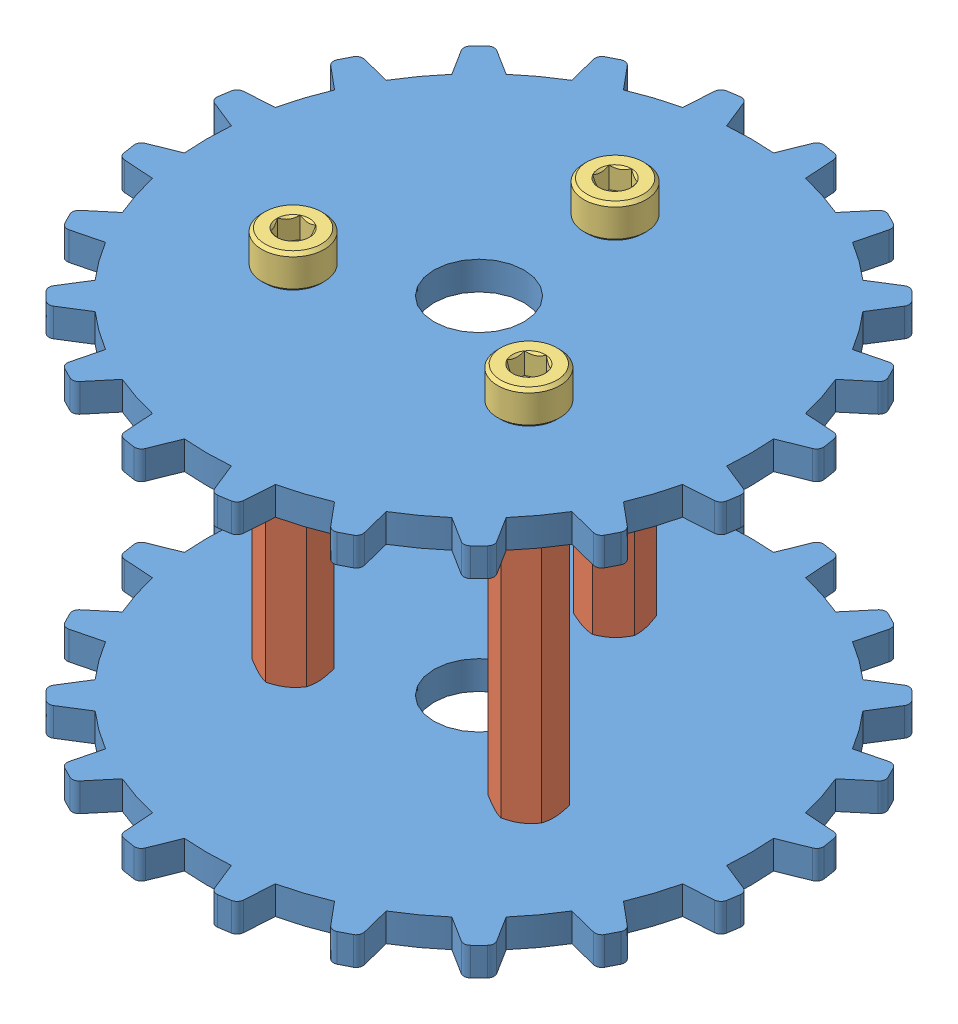
SolidWorks assembly DrivingWheelAssem, configuration Default. Lengths in mm.
Overall size (53.49 39.29 53.49).
11 component instances, 3 part files, 26 mates.
Components (placement in the parent):
- DrivingWheel-1: DrivingWheel [Default] at origin size (53.49 2.5 53.49)
- DrivingWheel-2: DrivingWheel [Default] at (0 30.5 0) size (53.49 2.5 53.49)
- M3_28MM_Standoff-1: M3_28MM_Standoff [95947A517] at (-10.3923 14 6) x (-0.440762 0 0.897624) z (0 -1 0) size (4.5 5.2 28.67)
- M3_8MM_SocketHead-1: M3_8MM_SocketHead [91292A112] at (-10.3923 22.5 6) x (0.889266 0 -0.457391) z (0 -1 0) size (5.5 5.5 11.58)
- M3_28MM_Standoff-2: M3_28MM_Standoff [95947A517] at (10.3923 14 6) x (-0.541432 0 -0.840745) z (0 -1 0) size (4.5 5.2 28.67)
- M3_8MM_SocketHead-2: M3_8MM_SocketHead [91292A112] at (10.3923 22.5 6) x (0.997541 0 0.070084) z (0 -1 0) size (5.5 5.5 11.58)
- M3_28MM_Standoff-3: M3_28MM_Standoff [95947A517] at (0 14 -12) x (-0.674924 0 -0.737887) z (0 -1 0) size (4.5 5.2 28.67)
- M3_8MM_SocketHead-3: M3_8MM_SocketHead [91292A112] at (0 22.5 -12) x (1 0 0) z (0 -1 0) size (5.5 5.5 11.58)
- M3_8MM_SocketHead-4: M3_8MM_SocketHead [91292A112] at (10.3923 5.5 6) x (1 0 0) z (0 1 0) size (5.5 5.5 11.58)
- M3_8MM_SocketHead-5: M3_8MM_SocketHead [91292A112] at (-10.3923 5.5 6) x (0.298331 0 0.954463) z (0 1 0) size (5.5 5.5 11.58)
- M3_8MM_SocketHead-6: M3_8MM_SocketHead [91292A112] at (0 5.5 -12) x (1 0 0) z (0 1 0) size (5.5 5.5 11.58)
Mates (geometry in assembly coordinates):
- Concentric1: concentric aligned: circle of DrivingWheel-1; circle of DrivingWheel-2
- Concentric2: concentric aligned: circle of DrivingWheel-1; circle of DrivingWheel-2
- Concentric3: concentric aligned: circle of DrivingWheel-1; circle of M3_28MM_Standoff-3
- Concentric4: concentric aligned: circle of DrivingWheel-1; circle of M3_28MM_Standoff-1
- Concentric5: concentric aligned: circle of DrivingWheel-1; circle of M3_28MM_Standoff-2
- Coincident3: coincident anti-aligned: plane of DrivingWheel-1 through (0 0 0) normal (0 1 0); plane of M3_28MM_Standoff-1 through (-12.7244 0 4.8549) normal (0 -1 0)
- Coincident4: coincident anti-aligned: plane of DrivingWheel-1 through (0 0 0) normal (0 1 0); plane of M3_28MM_Standoff-2 through (12.5766 0 4.5933) normal (0 -1 0)
- Coincident5: coincident anti-aligned: plane of DrivingWheel-1 through (0 0 0) normal (0 1 0); plane of M3_28MM_Standoff-3 through (1.9171 0 -13.7535) normal (0 -1 0)
- Coincident6: coincident anti-aligned: plane of DrivingWheel-2 through (0 28 0) normal (0 -1 0); plane of M3_28MM_Standoff-1 through (-12.7244 28 4.8549) normal (0 1 0)
- Coincident7: coincident anti-aligned: plane of DrivingWheel-2 through (0 30.5 0) normal (0 1 0); plane of M3_8MM_SocketHead-1 through (-10.3923 30.5 6) normal (0 -1 0)
- Concentric7: concentric anti-aligned: circle of DrivingWheel-2; circle of M3_8MM_SocketHead-2
- Coincident8: coincident anti-aligned: plane of DrivingWheel-2 through (0 30.5 0) normal (0 1 0); plane of M3_8MM_SocketHead-2 through (10.3923 30.5 6) normal (0 -1 0)
- Coincident9: coincident anti-aligned: plane of DrivingWheel-2 through (0 30.5 0) normal (0 1 0); plane of M3_8MM_SocketHead-3 through (0 30.5 -12) normal (0 -1 0)
- Concentric8: concentric aligned: circle of DrivingWheel-2; circle of M3_8MM_SocketHead-3
- Coincident10: coincident anti-aligned: plane of DrivingWheel-1 through (0 -2.5 0) normal (0 -1 0); plane of M3_8MM_SocketHead-4 through (10.3923 -2.5 6) normal (0 1 0)
- Concentric9: concentric anti-aligned: circle of DrivingWheel-1; circle of M3_8MM_SocketHead-4
- Coincident11: coincident anti-aligned: plane of DrivingWheel-1 through (0 -2.5 0) normal (0 -1 0); plane of M3_8MM_SocketHead-5 through (-10.3923 -2.5 6) normal (0 1 0)
- Coincident12: coincident anti-aligned: plane of DrivingWheel-1 through (0 -2.5 0) normal (0 -1 0); plane of M3_8MM_SocketHead-6 through (0 -2.5 -12) normal (0 1 0)
- Concentric10: concentric anti-aligned: circle of DrivingWheel-1; circle of M3_8MM_SocketHead-5
- Concentric11: concentric anti-aligned: circle of DrivingWheel-1; circle of M3_8MM_SocketHead-6
- Lock1: lock: unknown of M3_8MM_SocketHead-4; unknown of M3_8MM_SocketHead-6
- Lock2: lock: unknown of M3_8MM_SocketHead-4; unknown of M3_8MM_SocketHead-5
- Lock4: lock: unknown of M3_28MM_Standoff-1; unknown of M3_28MM_Standoff-2
- Lock5: lock: unknown of M3_28MM_Standoff-1; unknown of M3_28MM_Standoff-3
- Lock6: lock: unknown of M3_8MM_SocketHead-1; unknown of M3_8MM_SocketHead-3
- Lock7: lock: unknown of M3_8MM_SocketHead-1; unknown of M3_8MM_SocketHead-2
